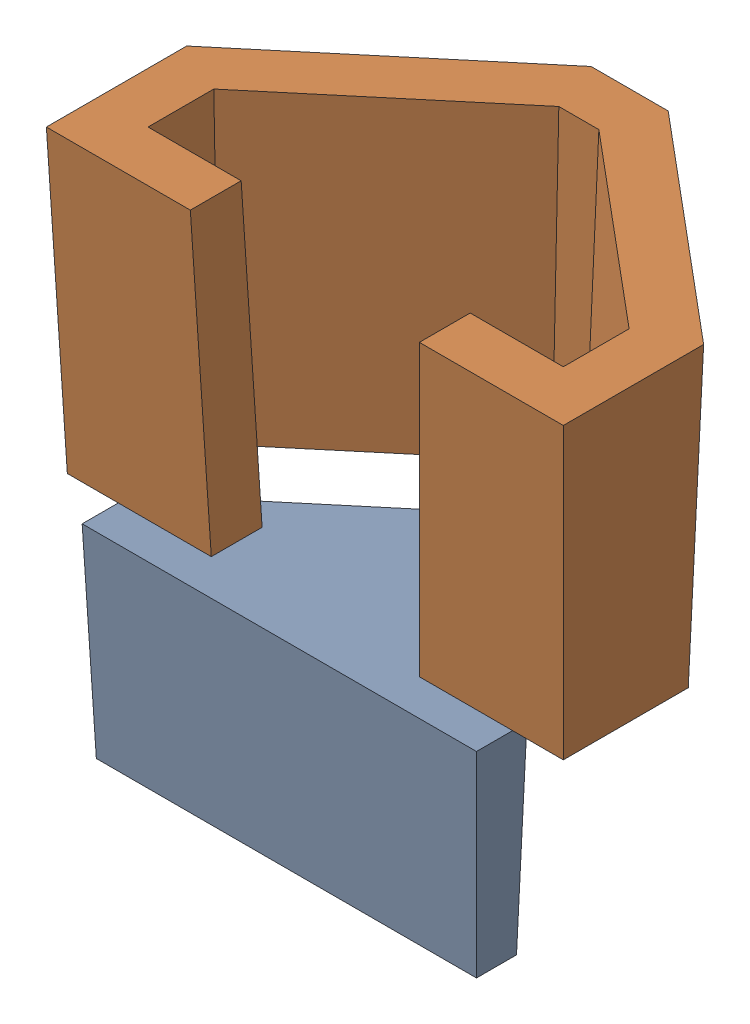
SolidWorks assembly Ensamblaje1, configuration Predeterminado. Lengths in mm.
Overall size (129.19 125.83 87.55).
2 component instances, 2 part files, 2 mates.
Components (placement in the parent):
- cabeza-1: cabeza [Predeterminado] at (-3.3799 -0.5383 -1.6344) x (1 0 0) z (0 1 0) size (98.55 50.55 50.8)
- molde_cabeza-2: molde_cabeza [Predeterminado] at (-5.1549 50.291 -21.5581) size (129.19 75 81.18)
Mates (geometry in assembly coordinates):
- Coincidente10: coincident anti-aligned: plane of cabeza-1 through (-3.3799 -0.5383 -1.6344) normal (-0.999391 -0.034899 0); plane of molde_cabeza-2 through (-3.4714 2.0806 -21.5581) normal (0.999391 0.034899 0)
- Coincidente11: coincident anti-aligned: plane of cabeza-1 through (91.6201 -0.5383 -11.6344) normal (0.999391 -0.034899 0); plane of molde_cabeza-2 through (95.0786 2.0806 -34.1581) normal (-0.999391 0.034899 0)
